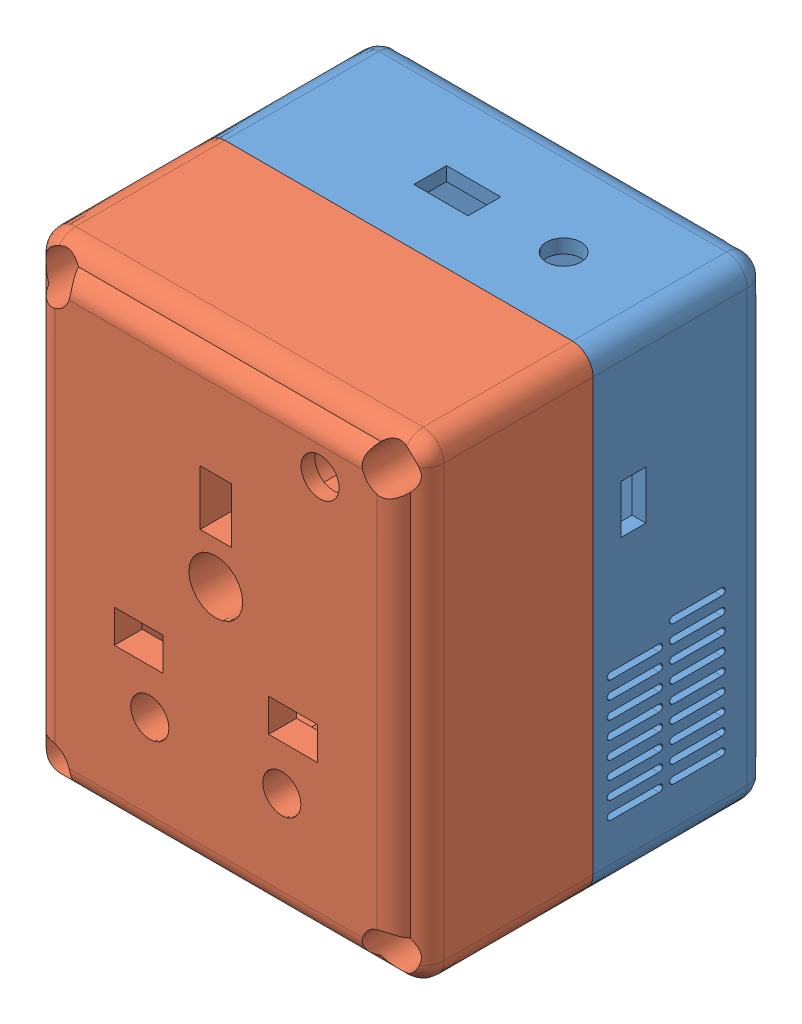
SolidWorks assembly Final, configuration Default. Lengths in mm.
Overall size (56 68 58.55).
2 component instances, 2 part files, 3 mates.
Components (placement in the parent):
- Front-1: Front [Default] at origin size (56 68 32.25)
- Behind-1: Behind [Default] at origin size (56 68 39.13)
Mates (geometry in assembly coordinates):
- Coincident1: coincident anti-aligned: plane of Front-1 through (0 0 0) normal (0 0 1); plane of Behind-1 through (0 0 0) normal (0 0 -1)
- Coincident2: coincident aligned: plane of Front-1 through (56 0 -25) normal (1 0 0); plane of Behind-1 through (56 0 24.3) normal (1 0 0)
- Coincident3: coincident aligned: plane of Front-1 through (0 68 -25) normal (0 1 0); plane of Behind-1 through (0 68 24.3) normal (0 1 0)
